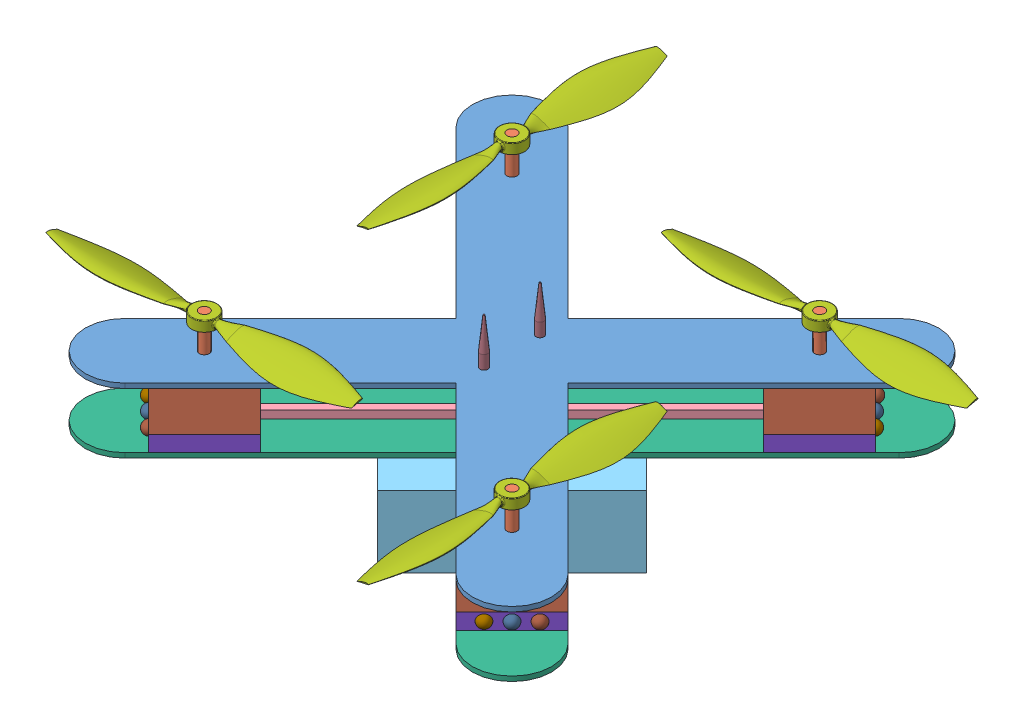
SolidWorks assembly CISAR, configuration Default. Lengths in mm.
Overall size (387.44 114.5 387.44).
39 component instances, 13 part files, 82 mates.
Components (placement in the parent):
- Top_Frame-2: Top_Frame [Default] at (19.4318 294 -6.2868) size (294 3 294)
- MotorDriverEnclosure-1: MotorDriverEnclosure [Default] at (-77.5682 269 -103.2868) x (-0.707107 0 -0.707107) z (0.707107 0 -0.707107) size (50 50 50)
- MotorDriverEnclosure-2: MotorDriverEnclosure [Default] at (116.4318 269 -103.2868) x (0.707107 0 -0.707107) z (0.707107 0 0.707107) size (50 50 50)
- MotorDriverEnclosure-3: MotorDriverEnclosure [Default] at (-77.5682 269 90.7132) x (-0.707107 0 0.707107) z (-0.707107 0 -0.707107) size (50 50 50)
- MotorDriverEnclosure-4: MotorDriverEnclosure [Default] at (116.4318 269 90.7132) x (0.707107 0 0.707107) z (-0.707107 0 0.707107) size (50 50 50)
- ControlCircuitsEnclosure-1: ControlCircuitsEnclosure [Default] at (19.4318 259 -6.2868) x (0.707107 0 0.707107) z (-0.707107 0 0.707107) size (50 35 50)
- ConnectingRod_5x5mm-1: ConnectingRod_5x5mm [Default] at (-30.8992 281.5 40.5087) x (0.707107 0 -0.707107) z (0.707107 0 0.707107) size (99 5 5)
- ConnectingRod_5x5mm-2: ConnectingRod_5x5mm [Default] at (-27.3636 281.5 -56.6177) x (0.707107 0 0.707107) z (-0.707107 0 0.707107) size (99 5 5)
- ConnectingRod_5x5mm-3: ConnectingRod_5x5mm [Default] at (66.2272 281.5 -56.6177) x (0.707107 0 -0.707107) z (0.707107 0 0.707107) size (99 5 5)
- ConnectingRod_5x5mm-4: ConnectingRod_5x5mm [Default] at (69.7627 281.5 40.5087) x (0.707107 0 0.707107) z (-0.707107 0 0.707107) size (99 5 5)
- BatteryEnclosure-1: BatteryEnclosure [Default] at (-15.9235 233.5 -41.6421) x (-0.707107 0 0.707107) z (0 1 0) size (120 100 45)
- Bottom_Frame-1: Bottom_Frame [Default] at (19.4318 256 -6.2868) size (294 3 294)
- User Library-7_5 inch prop (1)-1: User Library-7_5 inch prop (1) [Default] at (-77.5682 315.825 90.7132) x (-0.015378 0 -0.999882) z (0 -1 0) size (190.5 190.53 9.14)
- User Library-7_5 inch prop (1)-2: User Library-7_5 inch prop (1) [Default] at (116.4318 315.825 90.7132) x (-0.999882 0 0.015378) z (0 -1 0) size (190.5 190.53 9.14)
- User Library-7_5 inch prop (1)-3: User Library-7_5 inch prop (1) [Default] at (-77.5682 315.825 -103.2868) x (0.999882 0 -0.015378) z (0 -1 0) size (190.5 190.53 9.14)
- User Library-7_5 inch prop (1)-4: User Library-7_5 inch prop (1) [Default] at (116.4318 315.825 -103.2868) x (-0.015378 0 -0.999882) z (0 -1 0) size (190.5 190.53 9.14)
- MotorDriver-1: MotorDriver [Default] at (-77.5682 259 -103.2868) x (-0.707107 0 -0.707107) z (0.707107 0 -0.707107) size (50 10 50)
- MotorDriver-2: MotorDriver [Default] at (116.4318 259 90.7132) x (0.707107 0 0.707107) z (-0.707107 0 0.707107) size (50 10 50)
- MotorDriver-3: MotorDriver [Default] at (-77.5682 259 90.7132) x (-0.707107 0 0.707107) z (-0.707107 0 -0.707107) size (50 10 50)
- MotorDriver-4: MotorDriver [Default] at (116.4318 259 -103.2868) x (0.707107 0 -0.707107) z (0.707107 0 0.707107) size (50 10 50)
- ConnectingRod_5x5mm-5: ConnectingRod_5x5mm [Default] at (-30.8992 264 40.5087) x (0.707107 0 -0.707107) z (0.707107 0 0.707107) size (99 5 5)
- ConnectingRod_5x5mm-6: ConnectingRod_5x5mm [Default] at (69.7627 264 40.5087) x (0.707107 0 0.707107) z (-0.707107 0 0.707107) size (99 5 5)
- ConnectingRod_5x5mm-7: ConnectingRod_5x5mm [Default] at (-27.3636 264 -56.6177) x (0.707107 0 0.707107) z (-0.707107 0 0.707107) size (99 5 5)
- ConnectingRod_5x5mm-8: ConnectingRod_5x5mm [Default] at (66.2272 264 -56.6177) x (0.707107 0 -0.707107) z (0.707107 0 0.707107) size (99 5 5)
- Lights-1: Lights [Default] at (124.9171 264 116.8762) x (0.5 -0.707107 -0.5) z (-0.5 -0.707107 0.5) size (8 4 8)
- Lights-2: Lights [Default] at (142.5947 264 -111.772) x (0.569382 -0.592965 0.569382) z (0.41929 0.805228 0.41929) size (8 4 8)
- Lights-3: Lights [Default] at (-86.0535 264 -129.4497) x (0.5 0.707107 -0.5) z (-0.5 0.707107 0.5) size (8 4 8)
- Lights-4: Lights [Default] at (-103.7312 264 99.1985) x (0.5 0.707107 0.5) z (0.5 -0.707107 0.5) size (8 4 8)
- Camera-1: Camera [Default] at (134.1095 264 108.3909) x (0.5 -0.707107 -0.5) z (-0.5 -0.707107 0.5) size (8 4 8)
- Camera-2: Camera [Default] at (133.7559 264 -120.6109) x (0.5 -0.707107 0.5) z (0.5 0.707107 0.5) size (8 4 8)
- Camera-3: Camera [Default] at (-95.2459 264 -120.9644) x (0.5 0.707107 -0.5) z (-0.5 0.707107 0.5) size (8 4 8)
- Camera-4: Camera [Default] at (-94.8923 264 108.0374) x (0.5 0.707107 0.5) z (0.5 -0.707107 0.5) size (8 4 8)
- Distance-1: Distance [Default] at (142.9483 264 99.5521) x (0.5 -0.707107 -0.5) z (-0.5 -0.707107 0.5) size (8 4 8)
- Distance-2: Distance [Default] at (125.2706 264 -129.8033) x (0.5 -0.707107 0.5) z (0.5 0.707107 0.5) size (8 4 8)
- Distance-3: Distance [Default] at (-104.0847 264 -112.1256) x (0.5 0.707107 -0.5) z (-0.5 0.707107 0.5) size (8 4 8)
- Distance-4: Distance [Default] at (-86.0535 264 116.8762) x (0.5 0.707107 0.5) z (0.5 -0.707107 0.5) size (8 4 8)
- ConnectingRod_20x20mm-3: ConnectingRod_20x20mm [Default] at (19.4318 250 -6.2868) x (0.707107 0 0.707107) z (-0.707107 0 0.707107) size (20 15 20)
- Antennae-1: Antennae [Default] at (19.4318 295.5 -23.9644) size (5 30 5)
- Antennae-2: Antennae [Default] at (19.4318 295.5 11.3909) size (5 30 5)
Mates (geometry in assembly coordinates):
- Coincident11: coincident anti-aligned: plane of Top_Frame-2 through (141.4318 294 115.7132) normal (0 -1 0); plane of MotorDriverEnclosure-1 through (-77.5682 294 -103.2868) normal (0 1 0)
- Coincident12: coincident anti-aligned: plane of Top_Frame-2 through (141.4318 294 115.7132) normal (0 -1 0); plane of MotorDriverEnclosure-2 through (116.4318 294 -103.2868) normal (0 1 0)
- Coincident13: coincident anti-aligned: plane of Top_Frame-2 through (141.4318 294 115.7132) normal (0 -1 0); plane of MotorDriverEnclosure-4 through (116.4318 294 90.7132) normal (0 1 0)
- Coincident14: coincident anti-aligned: plane of Top_Frame-2 through (141.4318 294 115.7132) normal (0 -1 0); plane of MotorDriverEnclosure-3 through (-77.5682 294 90.7132) normal (0 1 0)
- Concentric2: concentric aligned: cylinder of Top_Frame-2 through (-77.5682 297 -103.2868) axis (0 -1 0) radius 3.15; cylinder of MotorDriverEnclosure-1 through (-77.5682 319 -103.2868) axis (0 -1 0) radius 3.15
- Coincident24: coincident aligned: plane of Top_Frame-2 through (-15.9235 297 -6.2868) normal (-0.707107 0 0.707107); plane of MotorDriverEnclosure-1 through (-77.5682 294 -67.9314) normal (-0.707107 0 0.707107)
- Concentric3: concentric aligned: cylinder of Top_Frame-2 through (116.4318 297 -103.2868) axis (0 -1 0) radius 3.15; cylinder of MotorDriverEnclosure-2 through (116.4318 319 -103.2868) axis (0 -1 0) radius 3.15
- Coincident26: coincident aligned: plane of Top_Frame-2 through (19.4318 297 -41.6421) normal (-0.707107 0 -0.707107); plane of MotorDriverEnclosure-2 through (81.0765 294 -103.2868) normal (-0.707107 0 -0.707107)
- Concentric4: concentric aligned: cylinder of Top_Frame-2 through (-77.5682 297 90.7132) axis (0 -1 0) radius 3.15; cylinder of MotorDriverEnclosure-3 through (-77.5682 319 90.7132) axis (0 -1 0) radius 3.15
- Coincident27: coincident aligned: plane of Top_Frame-2 through (-120.2459 297 98.0356) normal (-0.707107 0 -0.707107); plane of MotorDriverEnclosure-3 through (-77.5682 294 55.3579) normal (-0.707107 0 -0.707107)
- Coincident28: coincident anti-aligned: circle of Top_Frame-2; cylinder of MotorDriverEnclosure-4 through (116.4318 319 90.7132) axis (0 -1 0) radius 3.15
- Coincident30: coincident aligned: plane of Top_Frame-2 through (159.1095 297 98.0356) normal (0.707107 0 -0.707107); plane of MotorDriverEnclosure-4 through (116.4318 294 55.3579) normal (0.707107 0 -0.707107)
- Parallel8: parallel anti-aligned: plane of MotorDriverEnclosure-1 through (-42.2129 294 -103.2868) normal (0.707107 0 0.707107); plane of ControlCircuitsEnclosure-1 through (-15.9235 294 -6.2868) normal (-0.707107 0 -0.707107)
- Coincident48: coincident anti-aligned: plane of MotorDriverEnclosure-2 through (102.9968 269 -89.8517) normal (-0.707107 0 0.707107); plane of ConnectingRod_5x5mm-3 through (104.7645 279 -88.084) normal (0.707107 0 -0.707107)
- Coincident49: coincident aligned: line of MotorDriverEnclosure-2 through (104.7645 279 -88.084) axis (0 1 0); line of ConnectingRod_5x5mm-3 through (104.7645 279 -88.084) axis (0 1 0)
- Coincident50: coincident aligned: line of MotorDriverEnclosure-2 through (104.7645 284 -88.084) axis (-0.707107 0 -0.707107); line of ConnectingRod_5x5mm-3 through (104.7645 284 -88.084) axis (-0.707107 0 -0.707107)
- Coincident55: coincident anti-aligned: line of MotorDriverEnclosure-1 through (-62.3654 284 -91.6195) axis (-0.707107 0 0.707107); line of ConnectingRod_5x5mm-2 through (-65.9009 284 -88.084) axis (0.707107 0 -0.707107)
- Coincident58: coincident anti-aligned: plane of MotorDriverEnclosure-1 through (-64.1332 269 -89.8517) normal (0.707107 0 0.707107); plane of ConnectingRod_5x5mm-2 through (-65.9009 279 -88.084) normal (-0.707107 0 -0.707107)
- Parallel16: parallel anti-aligned: plane of ControlCircuitsEnclosure-1 through (5.9968 259 -19.7218) normal (-0.707107 0 -0.707107); plane of ConnectingRod_5x5mm-2 through (4.1026 279 -18.0804) normal (0.707107 0 0.707107)
- Coincident60: coincident: point of MotorDriverEnclosure-1; point of ConnectingRod_5x5mm-2
- Coincident65: coincident anti-aligned: plane of ControlCircuitsEnclosure-1 through (19.4318 259 -6.2868) normal (0 -1 0); plane of Bottom_Frame-1 through (141.4318 259 115.7132) normal (0 1 0)
- Coincident115: coincident anti-aligned: circle of MotorDriverEnclosure-3; circle of User Library-7_5 inch prop (1)-1
- Coincident116: coincident anti-aligned: circle of MotorDriverEnclosure-4; circle of User Library-7_5 inch prop (1)-2
- Coincident118: coincident anti-aligned: circle of MotorDriverEnclosure-2; circle of User Library-7_5 inch prop (1)-4
- Coincident119: coincident anti-aligned: circle of MotorDriverEnclosure-1; circle of User Library-7_5 inch prop (1)-3
- Parallel21: parallel anti-aligned: line of User Library-7_5 inch prop (1)-2 through (211.6705 315.825 89.2485) axis (-0.999882 0 0.015378); line of User Library-7_5 inch prop (1)-3 through (-172.8069 315.825 -101.822) axis (0.999882 0 -0.015378)
- Parallel22: parallel aligned: line of User Library-7_5 inch prop (1)-1 through (-76.1035 315.825 185.952) axis (-0.015378 0 -0.999882); line of User Library-7_5 inch prop (1)-4 through (117.8965 315.825 -8.048) axis (-0.015378 0 -0.999882)
- Perpendicular2: perpendicular: line of User Library-7_5 inch prop (1)-2 through (211.6705 315.825 89.2485) axis (-0.999882 0 0.015378); line of User Library-7_5 inch prop (1)-4 through (117.8965 315.825 -8.048) axis (-0.015378 0 -0.999882)
- Coincident129: coincident: point of MotorDriverEnclosure-4; point of MotorDriver-2
- Parallel26: parallel aligned: plane of MotorDriverEnclosure-4 through (116.4318 294 126.0686) normal (0.707107 0 0.707107); plane of MotorDriver-2 through (116.4318 269 126.0686) normal (0.707107 0 0.707107)
- Parallel27: parallel aligned: line of Top_Frame-2 through (54.7871 297 -6.2868) axis (0.707107 0 -0.707107); line of Bottom_Frame-1 through (54.7871 259 -6.2868) axis (0.707107 0 -0.707107)
- Parallel31: parallel aligned: plane of Top_Frame-2 through (141.4318 297 115.7132) normal (0 1 0); plane of Bottom_Frame-1 through (141.4318 259 115.7132) normal (0 1 0)
- Coincident143: coincident anti-aligned: plane of Top_Frame-2 through (141.4318 294 115.7132) normal (0 -1 0); plane of ControlCircuitsEnclosure-1 through (19.4318 294 -6.2868) normal (0 1 0)
- Parallel33: parallel aligned: plane of MotorDriverEnclosure-3 through (-77.5682 294 55.3579) normal (0.707107 0 -0.707107); plane of MotorDriver-3 through (-77.5682 269 55.3579) normal (0.707107 0 -0.707107)
- Parallel34: parallel aligned: plane of Bottom_Frame-1 through (141.4318 259 115.7132) normal (0 1 0); plane of MotorDriver-3 through (-77.5682 269 90.7132) normal (0 1 0)
- Coincident147: coincident: point of MotorDriverEnclosure-3; point of MotorDriver-3
- Parallel35: parallel aligned: plane of Bottom_Frame-1 through (141.4318 259 115.7132) normal (0 1 0); plane of MotorDriver-1 through (-77.5682 269 -103.2868) normal (0 1 0)
- Parallel36: parallel aligned: plane of MotorDriverEnclosure-1 through (-42.2129 294 -103.2868) normal (0.707107 0 0.707107); plane of MotorDriver-1 through (-42.2129 269 -103.2868) normal (0.707107 0 0.707107)
- Coincident150: coincident: point of MotorDriverEnclosure-1; point of MotorDriver-1
- Parallel38: parallel aligned: plane of Bottom_Frame-1 through (141.4318 259 115.7132) normal (0 1 0); plane of MotorDriver-4 through (116.4318 269 -103.2868) normal (0 1 0)
- Parallel39: parallel aligned: plane of MotorDriverEnclosure-2 through (81.0765 294 -103.2868) normal (-0.707107 0 -0.707107); plane of MotorDriver-4 through (81.0765 269 -103.2868) normal (-0.707107 0 -0.707107)
- Coincident154: coincident: point of MotorDriverEnclosure-2; point of MotorDriver-4
- Parallel40: parallel aligned: plane of MotorDriverEnclosure-3 through (-42.2129 294 90.7132) normal (0.707107 0 0.707107); plane of ConnectingRod_5x5mm-1 through (-27.3636 281.5 44.0442) normal (0.707107 0 0.707107)
- Parallel41: parallel aligned: plane of Top_Frame-2 through (141.4318 297 115.7132) normal (0 1 0); plane of ConnectingRod_5x5mm-1 through (-62.3654 284 79.046) normal (0 1 0)
- Coincident158: coincident: point of MotorDriverEnclosure-3; point of ConnectingRod_5x5mm-1
- Parallel42: parallel aligned: plane of ConnectingRod_5x5mm-4 through (31.2254 284 9.0424) normal (0 1 0); plane of Bottom_Frame-1 through (141.4318 259 115.7132) normal (0 1 0)
- Parallel43: parallel aligned: plane of MotorDriverEnclosure-4 through (116.4318 294 55.3579) normal (0.707107 0 -0.707107); plane of ConnectingRod_5x5mm-4 through (69.7627 281.5 40.5087) normal (0.707107 0 -0.707107)
- Coincident162: coincident: point of MotorDriverEnclosure-4; point of ConnectingRod_5x5mm-4
- Parallel44: parallel aligned: plane of ConnectingRod_5x5mm-3 through (69.7627 281.5 -53.0822) normal (0.707107 0 0.707107); plane of ConnectingRod_5x5mm-8 through (69.7627 264 -53.0822) normal (0.707107 0 0.707107)
- Parallel45: parallel aligned: plane of ConnectingRod_5x5mm-3 through (34.761 284 -18.0804) normal (0 1 0); plane of ConnectingRod_5x5mm-8 through (34.761 266.5 -18.0804) normal (0 1 0)
- Coincident165: coincident: point of MotorDriver-4; point of ConnectingRod_5x5mm-8
- Parallel46: parallel aligned: plane of ConnectingRod_5x5mm-2 through (-65.9009 284 -88.084) normal (0 1 0); plane of ConnectingRod_5x5mm-7 through (-65.9009 266.5 -88.084) normal (0 1 0)
- Parallel47: parallel aligned: plane of ConnectingRod_5x5mm-2 through (-27.3636 281.5 -56.6177) normal (0.707107 0 -0.707107); plane of ConnectingRod_5x5mm-7 through (-27.3636 264 -56.6177) normal (0.707107 0 -0.707107)
- Coincident168: coincident: point of MotorDriver-1; point of ConnectingRod_5x5mm-7
- Parallel48: parallel aligned: plane of ConnectingRod_5x5mm-1 through (-62.3654 284 79.046) normal (0 1 0); plane of ConnectingRod_5x5mm-5 through (-62.3654 266.5 79.046) normal (0 1 0)
- Parallel49: parallel aligned: plane of ConnectingRod_5x5mm-1 through (-27.3636 281.5 44.0442) normal (0.707107 0 0.707107); plane of ConnectingRod_5x5mm-5 through (-27.3636 264 44.0442) normal (0.707107 0 0.707107)
- Coincident171: coincident: point of MotorDriver-3; point of ConnectingRod_5x5mm-5
- Parallel50: parallel aligned: plane of ConnectingRod_5x5mm-4 through (31.2254 284 9.0424) normal (0 1 0); plane of ConnectingRod_5x5mm-6 through (31.2254 266.5 9.0424) normal (0 1 0)
- Parallel51: parallel anti-aligned: plane of ConnectingRod_5x5mm-4 through (69.7627 281.5 40.5087) normal (0.707107 0 -0.707107); plane of ConnectingRod_5x5mm-6 through (66.2272 264 44.0442) normal (-0.707107 0 0.707107)
- Coincident174: coincident: point of MotorDriver-2; point of ConnectingRod_5x5mm-6
- Parallel55: parallel anti-aligned: plane of MotorDriver-2 through (124.9171 264 116.8762) normal (0.707107 0 0.707107); plane of Lights-1 through (124.9171 264 116.8762) normal (-0.707107 0 -0.707107)
- Coincident185: coincident anti-aligned: circle of MotorDriver-2; circle of Lights-1
- Coincident186: coincident anti-aligned: circle of MotorDriver-4; circle of Lights-2
- Coincident187: coincident anti-aligned: circle of MotorDriver-1; circle of Lights-3
- Coincident188: coincident anti-aligned: circle of MotorDriver-3; circle of Lights-4
- Coincident189: coincident anti-aligned: circle of MotorDriver-2; circle of Camera-1
- Coincident190: coincident anti-aligned: circle of MotorDriver-2; circle of Distance-1
- Coincident191: coincident anti-aligned: circle of MotorDriver-4; circle of Camera-2
- Coincident192: coincident anti-aligned: circle of MotorDriver-4; circle of Distance-2
- Coincident193: coincident anti-aligned: circle of MotorDriver-1; circle of Camera-3
- Coincident194: coincident anti-aligned: circle of MotorDriver-1; circle of Distance-3
- Coincident195: coincident anti-aligned: circle of MotorDriver-3; circle of Camera-4
- Coincident196: coincident anti-aligned: circle of MotorDriver-3; circle of Distance-4
- Coincident198: coincident anti-aligned: plane of BatteryEnclosure-1 through (97.2135 256 -13.3578) normal (0 1 0); plane of Bottom_Frame-1 through (141.4318 256 115.7132) normal (0 -1 0)
- Parallel57: parallel aligned: plane of Bottom_Frame-1 through (141.4318 256 115.7132) normal (0 -1 0); plane of ConnectingRod_20x20mm-3 through (19.4318 250 -6.2868) normal (0 -1 0)
- Parallel58: parallel: line of Bottom_Frame-1 through (5.2897 256 -6.2868) axis (0.707107 0 0.707107); plane of ConnectingRod_20x20mm-3 through (5.2897 265 -6.2868) normal (-0.707107 0 0.707107)
- Parallel59: parallel aligned: plane of Bottom_Frame-1 through (141.4318 256 115.7132) normal (0 -1 0); plane of ConnectingRod_20x20mm-3 through (19.4318 250 -6.2868) normal (0 -1 0)
- Coincident202: coincident: point of ControlCircuitsEnclosure-1; point of ConnectingRod_20x20mm-3
- Coincident203: coincident: point of BatteryEnclosure-1; point of ConnectingRod_20x20mm-3
- Parallel60: parallel: plane of BatteryEnclosure-1 through (54.7871 233.5 29.0686) normal (0.707107 0 0.707107); line of Bottom_Frame-1 through (-84.8905 256 133.3909) axis (0.707107 0 -0.707107)
- Coincident206: coincident aligned: circle of Top_Frame-2; circle of Antennae-1
- Coincident207: coincident aligned: circle of Top_Frame-2; circle of Antennae-2
